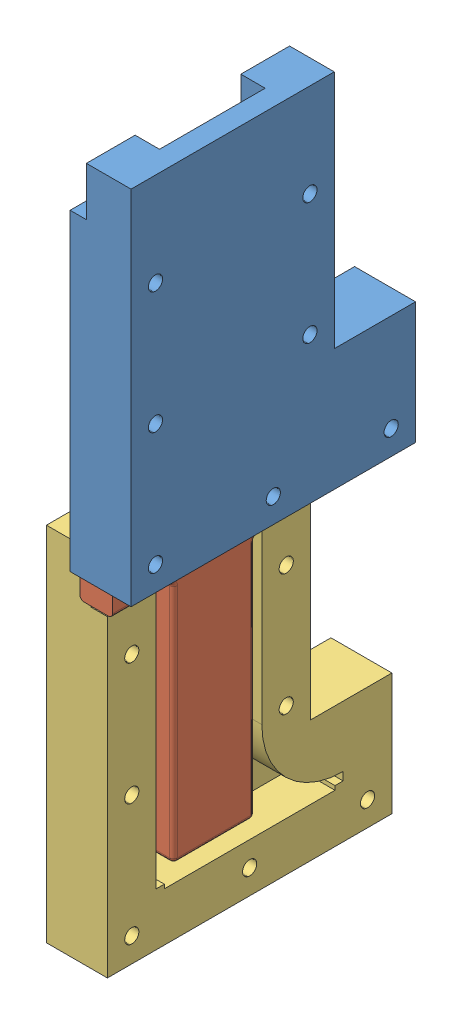
SolidWorks assembly Assem2, configuration ﾃﾞﾌｫﾙﾄ. Lengths in mm.
Overall size (27.26 177.46 76.44).
3 component instances, 3 part files, 1 mates.
Components (placement in the parent):
- gripper_outside4_right-1: gripper_outside4_right [ﾃﾞﾌｫﾙﾄ] at (-36.2303 89.5072 95.8021) size (15 89 70)
- gripper_inside4-1: gripper_inside4 [ﾃﾞﾌｫﾙﾄ] at (-25.2303 39.8021 89.3759) x (0 0 -1) z (1 0 0) size (50 82 8)
- gripper_outside4_left-1: gripper_outside4_left [ﾃﾞﾌｫﾙﾄ] at (-33.4891 1.0509 89.3647) size (15 89 70)
Mates (geometry in assembly coordinates):
- 一致2: coincident anti-aligned: plane of gripper_outside4_right-1 through (-17.2303 89.5072 95.8021) normal (-1 0 0); plane of gripper_inside4-1 through (-17.2303 39.8021 89.3759) normal (1 0 0)
